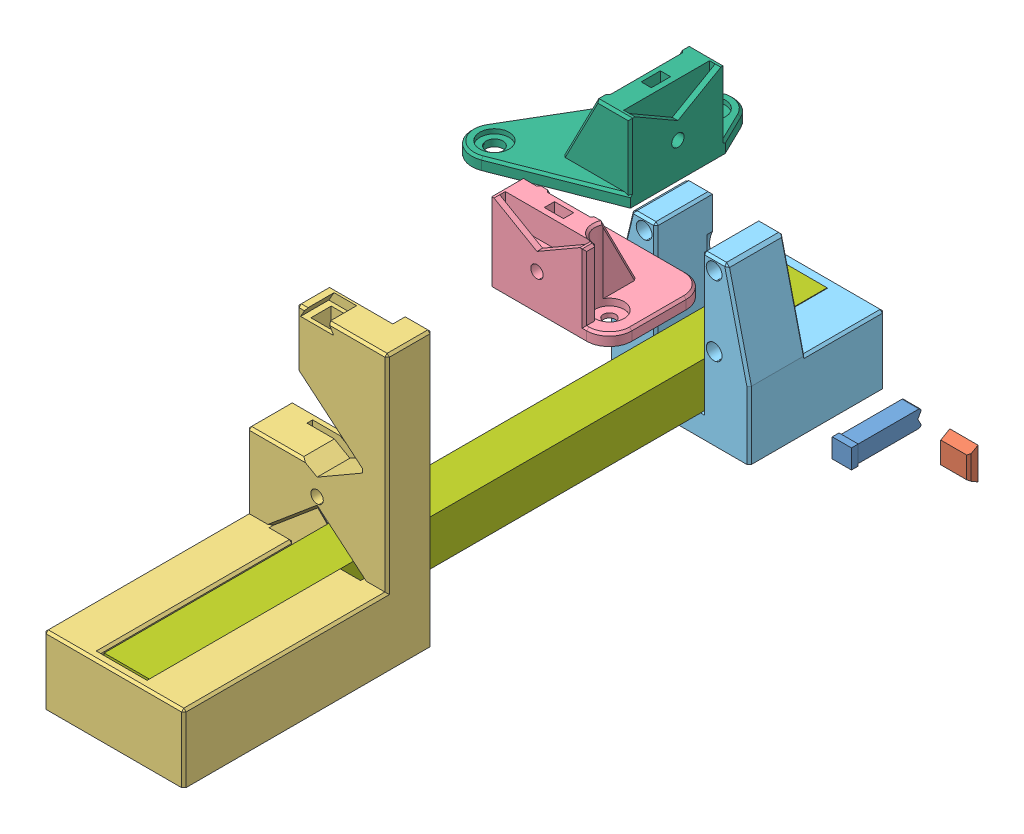
SolidWorks assembly Assembly, configuration Default. Lengths in mm.
Overall size (236.42 142.18 381.64).
7 component instances, 7 part files, 10 mates.
Components (placement in the parent):
- Clamp Bar long v1-1: Clamp Bar long v1 [Default] at (4.0362 12.8708 37.8753) size (8.5 8.5 31.27)
- Dovetail Cap-1: Dovetail Cap [Default] at (20.6223 0.9056 5.4427) size (12.5 14.12 4)
- E End Mount-1: E End Mount [Default] at (-19.3643 6.491 304.5) x (0 0 -1) z (0 1 0) size (110 62 121)
- E Slide Mount-1: E Slide Mount [Default] at (-46.9728 98.8511 72.0731) x (0 0 1) z (0 1 0) size (44 64 34.4)
- E Stepper Mount-1: E Stepper Mount [Default] at (-80.1143 6.491 -4.5) x (0 0 1) z (0 1 0) size (60 62 72)
- X Motor Slide Mount-1: X Motor Slide Mount [Default] at (-157.3022 12.3256 -58.1415) size (61 34.05 80.2)
- Part5^Assembly-1: Part5^Assembly [Default] at origin size (20 20 300) (virtual)
Mates (geometry in assembly coordinates):
- InPlace2: in place: plane of Part5^Assembly-1 through (0 0 0) normal (0 0 1); moOrthogonalPlaneRef_w of Part5^Assembly-1 through (0 0 0) normal (0 1 0); plane of Part5^Assembly-1 through (0 0 0) normal (1 0 0); unknown of Part5^Assembly-1
- Coincident4: coincident aligned: 
- Coincident5: coincident aligned: plane of Part5^Assembly-1 through (0 0 0) normal (0 1 0)
- Coincident6: coincident anti-aligned: plane of Part5^Assembly-1 through (0 0 0) normal (1 0 0)
- Coincident7: coincident anti-aligned: plane of E Stepper Mount-1 through (-59.3643 95.6561 0) normal (0 0 1); plane of Part5^Assembly-1 through (0 0 0) normal (0 0 -1)
- Coincident10: coincident aligned: line of E Stepper Mount-1 through (-59.3643 36.491 0) axis (1 0 0); line of Part5^Assembly-1 through (20 -59.1143 36.491) axis (0 1 0)
- Coincident12: coincident: point of E Stepper Mount-1; unknown of Part5^Assembly-1
- Coincident13: coincident aligned: plane of E End Mount-1 through (-81.3643 36.491 304.5) normal (0 1 0); plane of Part5^Assembly-1 through (-59.1143 36.491 300) normal (0 1 0)
- Coincident19: coincident anti-aligned: line of E End Mount-1 through (-39.1143 36.491 215.5) axis (0 0 1); line of Part5^Assembly-1 through (-39.1143 36.491 300) axis (0 0 -1)
- Coincident20: coincident anti-aligned: plane of E End Mount-1 through (-19.3643 6.491 300) normal (0 0 -1); plane of Part5^Assembly-1 through (0 0 300) normal (0 0 1)
